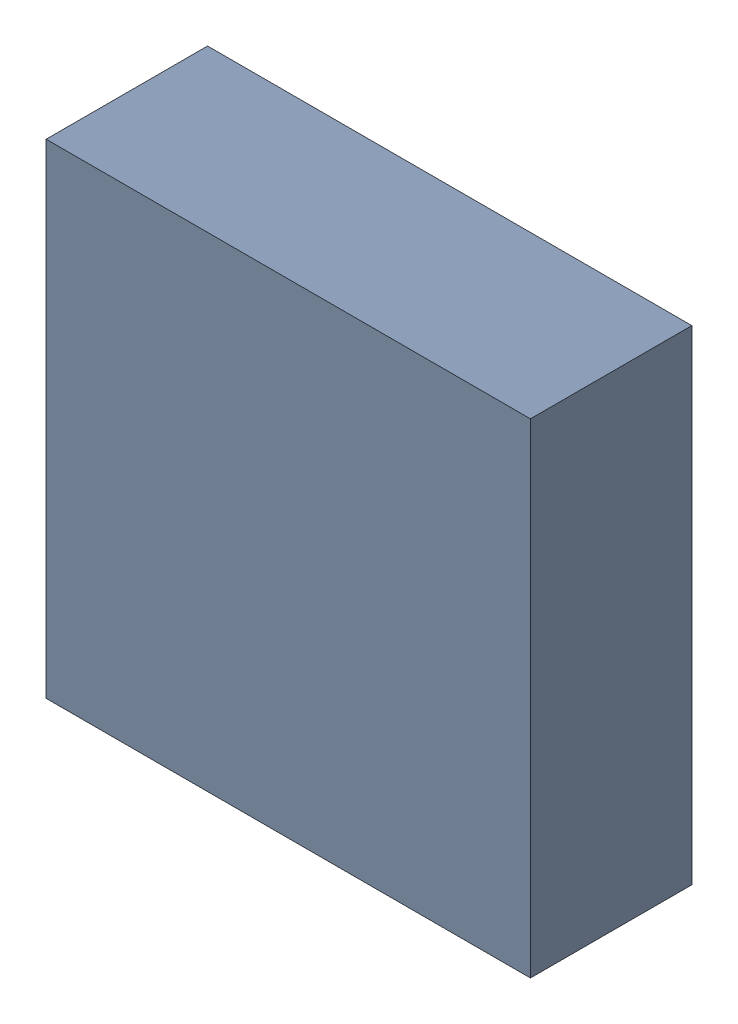
SolidWorks assembly S300_1v2(2)^MTi-1-SoB_v2, configuration Default. Lengths in mm.
Overall size (3 3 1).
2 component instances, 1 part files, 0 mates.
Components (placement in the parent):
- 6752205952(2)^S300_1v2(2)_MTi-1-SoB_v2-1: 6752205952(2)^S300_1v2(2)_MTi-1-SoB_v2 [Default] at (8.4999 8.8999 0) size (3 3 1)
  - Extruded-1(2)^6752205952(2)_S300_1v2(2)_MTi-1-SoB_v2-1: Extruded-1(2)^6752205952(2)_S300_1v2(2)_MTi-1-SoB_v2 [Default] at origin size (3 3 1)
